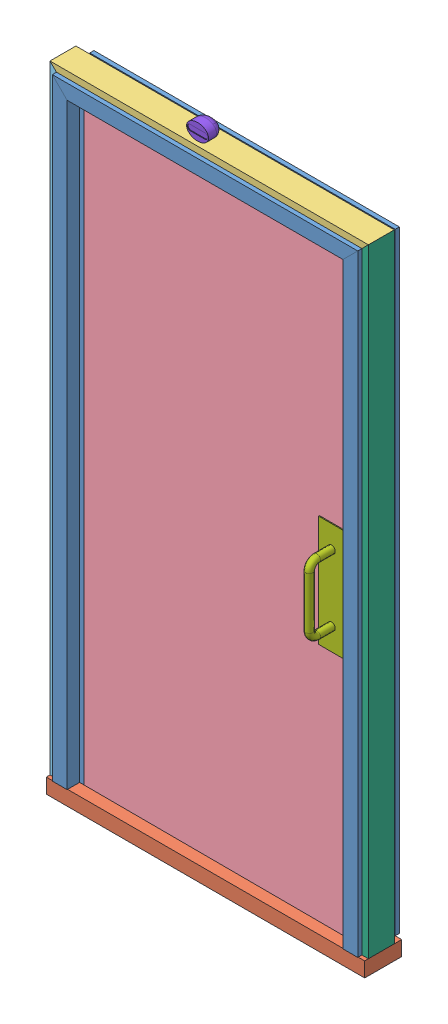
SolidWorks assembly Door36, configuration Default. Lengths in mm.
Overall size (1092.2 2284.92 194.69).
8 component instances, 8 part files, 21 mates.
Components (placement in the parent):
- Door Frame 36-1: Door Frame 36 [Default] at (321.9129 35.5703 1648.7335) size (1047.75 2098.68 142.88)
- Steel Tube Base 36-1: Steel Tube Base 36 [Default] at (233.0129 -15.2297 1690.0085) size (1092.2 50.8 127)
- Steel Tube Top 36-1: Steel Tube Top 36 [Default] at (296.5129 2092.9703 1588.4085) size (1092.2 63.5 88.9)
- Door 36-1: Door 36 [Default] at (1895.2773 33.1774 1653.2955) x (-0.999996 0 -0.002899) z (0.002899 0 -0.999996) size (914.4 2032 44.45)
- Steel Tube Left-1: Steel Tube Left [Default] at (233.0129 35.5703 1588.4085) size (63.5 2120.9 88.9)
- Steel Tube Right-1: Steel Tube Right [Default] at (1261.7129 35.5703 1588.4085) size (63.5 2120.9 88.9)
- DOOR32_HNDL-1: DOOR32_HNDL [Default] at (1175.9843 1051.5703 1651.2099) x (0.999996 0 0.002899) z (-0.002899 0 0.999996) size (88.9 381 139.7)
- Low Profile Forklift Red Light-1: Low Profile Forklift Red Light [Default] at (779.1129 2239.0203 1664.1005) size (75.19 61.34 53.09)
Mates (geometry in assembly coordinates):
- Coincident3: coincident anti-aligned: plane of Door Frame 36-1 through (296.5129 35.5703 1677.3085) normal (0 0 -1); plane of Steel Tube Left-1 through (233.0129 35.5703 1677.3085) normal (0 0 1)
- Coincident4: coincident anti-aligned: plane of Door Frame 36-1 through (296.5129 35.5703 1563.0085) normal (-1 0 0); plane of Steel Tube Left-1 through (296.5129 2092.9703 1677.3085) normal (1 0 0)
- Coincident5: coincident anti-aligned: plane of Door Frame 36-1 through (1261.7129 2141.0128 1563.0085) normal (1 0 0); plane of Steel Tube Right-1 through (1261.7129 35.5703 1677.3085) normal (-1 0 0)
- Coincident6: coincident anti-aligned: plane of Door Frame 36-1 through (1261.7129 2141.0128 1677.3085) normal (0 0 -1); plane of Steel Tube Right-1 through (1261.7129 35.5703 1677.3085) normal (0 0 1)
- Coincident7: coincident anti-aligned: plane of Door Frame 36-1 through (248.4704 2092.9703 1563.0085) normal (0 1 0); plane of Steel Tube Top 36-1 through (296.5129 2092.9703 1677.3085) normal (0 -1 0)
- Coincident8: coincident anti-aligned: plane of Steel Tube Top 36-1 through (1261.7129 2092.9703 1677.3085) normal (0.707107 -0.707107 0); plane of Steel Tube Right-1 through (1261.7129 2092.9703 1677.3085) normal (-0.707107 0.707107 0)
- Coincident9: coincident anti-aligned: plane of Steel Tube Top 36-1 through (233.0129 2156.4703 1677.3085) normal (-0.707107 -0.707107 0); plane of Steel Tube Left-1 through (233.0129 2156.4703 1677.3085) normal (0.707107 0.707107 0)
- Coincident10: coincident anti-aligned: plane of Door Frame 36-1 through (248.4704 2092.9703 1677.3085) normal (0 0 -1); plane of Steel Tube Top 36-1 through (296.5129 2092.9703 1677.3085) normal (0 0 1)
- Coincident11: coincident aligned: line of Steel Tube Top 36-1 through (233.0129 2156.4703 1677.3085) axis (0 0 -1); line of Steel Tube Left-1 through (233.0129 2156.4703 1677.3085) axis (0 0 -1)
- Coincident12: coincident aligned: line of Steel Tube Top 36-1 through (1325.2129 2156.4703 1677.3085) axis (0 0 -1); line of Steel Tube Right-1 through (1325.2129 2156.4703 1677.3085) axis (0 0 -1)
- Coincident13: coincident anti-aligned: plane of Steel Tube Base 36-1 through (1325.2129 35.5703 1690.0085) normal (0 1 0); plane of Steel Tube Right-1 through (1325.2129 35.5703 1677.3085) normal (0 -1 0)
- Coincident14: coincident anti-aligned: line of Steel Tube Base 36-1 through (1325.2129 35.5703 1563.0085) axis (0 0 1); line of Steel Tube Right-1 through (1325.2129 35.5703 1677.3085) axis (0 0 -1)
- Coincident17: coincident anti-aligned: plane of Steel Tube Base 36-1 through (1325.2129 35.5703 1690.0085) normal (0 1 0); plane of Door 36-1 through (1236.438 35.5703 1606.935) normal (0 -1 0)
- Coincident18: coincident aligned: line of Door Frame 36-1 through (1302.9879 35.5703 1563.0085) axis (-1 0 0); line of Steel Tube Base 36-1 through (1325.2129 35.5703 1563.0085) axis (-1 0 0)
- Coincident20: coincident aligned: line of Door Frame 36-1 through (321.9129 35.5703 1648.7335) axis (0 1 0); line of Door 36-1 through (321.9129 35.5703 1648.7335) axis (0 1 0)
- Coincident21: coincident anti-aligned: plane of Door 36-1 through (1895.4062 33.1774 1608.8457) normal (0.002899 0 -0.999996); plane of DOOR32_HNDL-1 through (1176.1132 1051.5703 1606.7601) normal (-0.002899 0 0.999996)
- Concentric1: concentric anti-aligned: cylinder of Door 36-1 through (1175.9843 1051.5703 1651.2099) axis (0.002899 0 -0.999996) radius 26.9875; cylinder of DOOR32_HNDL-1 through (1176.1132 1051.5703 1606.7601) axis (-0.002899 0 0.999996) radius 26.9875
- Parallel1: parallel anti-aligned: line of Door 36-1 through (1236.3091 35.5703 1651.3848) axis (-0.999996 0 -0.002899); line of DOOR32_HNDL-1 through (1131.5345 861.0703 1651.081) axis (0.999996 0 0.002899)
- Coincident22: coincident anti-aligned: plane of Low Profile Forklift Red Light-1 through (779.1129 2239.0203 1664.1005) normal (0 0 -1)
- Distance1: distance = 546.1 mm: plane of Low Profile Forklift Red Light-1 through (779.1129 2239.0203 1664.1005) normal (1 0 0); line of Steel Tube Left-1 through (233.0129 2156.4703 1677.3085) axis (0 0 -1)
- Distance2: distance = 82.55 mm aligned: plane of Low Profile Forklift Red Light-1 through (779.1129 2239.0203 1664.1005) normal (0 1 0); plane of Steel Tube Top 36-1 through (1325.2129 2156.4703 1677.3085) normal (0 1 0)
